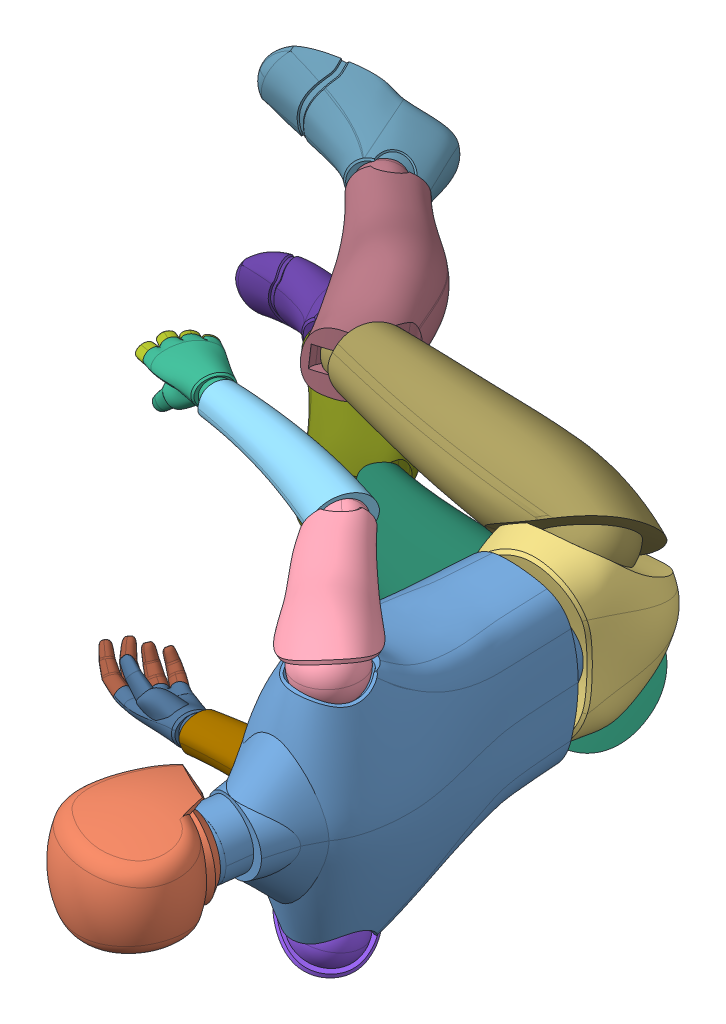
SolidWorks assembly Articulated_Dummy, configuration Default. Lengths in mm.
Overall size (1080.62 622.28 1340.25).
19 component instances, 17 part files, 18 mates.
Components (placement in the parent):
- Torso-1: Torso [Default] at origin size (276.17 406.18 676.75)
- Head-1: Head [Default] at (272.4966 0 13.9002) x (0.984808 0 0.173648) z (-0.173648 0 0.984808) size (223.51 154.11 248.99)
- Pelvis-1: Pelvis [Default] at (-175.9416 -0.0047 21.1469) x (0.984808 0 -0.173648) z (0.173648 0 0.984808) size (220.9 294.19 237.82)
- UpperArm_R-1: UpperArm_R [Default] at (-967.4121 -31.8704 494.9868) x (0.686668 0.032226 -0.726256) z (0.725991 0.021461 0.68737) size (145.29 112.21 352.1)
- LowerArm_R-1: LowerArm_R [Default] at (-1163.8165 -131.5552 990.6603) x (0.282282 -0.015764 -0.959202) z (0.953344 0.116147 0.278649) size (97.1 110.82 304.02)
- Hand_R-1: Hand_R [Default] at (-1071.8641 -48.9337 667.7427) x (0.586634 0.138363 -0.797945) z (0.805428 0.00317 0.592685) size (143.51 200.25 239.15)
  - Hand_R-1: Hand_R [Default] at origin size (143.51 200.25 232.94)
  - Fingers_R-1: Fingers_R [Default] at origin size (103.08 62.21 73.67)
- UpperArm_L-1: UpperArm_L [Default] at (-963.6086 40.2091 492.5524) x (0.655397 -0.202373 -0.727667) z (0.740186 -0.019578 0.672117) size (149.95 126.7 354.11)
- LowerArm_L-1: LowerArm_L [Default] at (-1215.8864 -1.0102 1100.795) x (0.200712 0.118224 -0.972491) z (0.979571 -0.01162 0.200761) size (97.1 110.82 304.02)
- Hand_L-1: Hand_L [Default] at (-1163.1688 -95.7629 792.4915) x (0.487614 -0.083042 -0.869101) z (0.870629 0.120485 0.476958) size (143.54 200.25 239.15)
  - Hand_L-1: Hand_L [Default] at origin size (143.54 200.25 232.94)
  - Fingers_L-1: Fingers_L [Default] at origin size (103.08 62.28 73.68)
- UpperLeg_R-1: UpperLeg_R [Default] at (-874.2977 48.5468 874.3966) x (0.108908 -0.602397 -0.790732) z (0.990819 0.001682 0.135184) size (212.64 165.47 563.01)
- LowerLeg_R-1: LowerLeg_R [Default] at (-712.3034 -40.8146 511.4118) x (0.771505 0.113631 -0.625994) z (0.620305 0.084374 0.77981) size (159.05 194.06 506.09)
- Foot_R-1: Foot_R [Default] at (-721.4345 -28.8172 498.7546) x (0.899051 -0.06744 -0.432619) z (0.434787 0.020963 0.900289) size (250.01 160.41 191.51)
- UpperLeg_L-1: UpperLeg_L [Default] at (-872.8456 -21.2577 898.3064) x (0.106044 0.59845 -0.794111) z (0.99355 -0.031522 0.108922) size (212.64 165.47 563.01)
- LowerLeg_L-1: LowerLeg_L [Default] at (-745.7676 -14.2143 531.1085) x (0.689228 -0.309105 -0.655301) z (0.704606 0.075229 0.7056) size (159.05 194.91 471.32)
- Foot_L-1: Foot_L [Default] at (-717.1717 -4.9666 523.6228) x (0.96643 -0.093697 -0.239235) z (0.236502 -0.039427 0.970831) size (250.8 160.43 191.19)
Mates (geometry in assembly coordinates):
- Coincident1: coincident: point of Torso-1; point of Head-1
- Parallel1: parallel aligned: plane of Head-1 through (272.4966 0 13.9002) normal (0 1 0)
- LimitAngle1: limit planar angle = 0.174533 rad aligned: plane of Head-1 through (272.4966 0 13.9002) normal (-0.173648 0 0.984808)
- Coincident5: coincident: point of Torso-1; point of Pelvis-1
- Parallel3: parallel aligned: plane of Pelvis-1 through (-175.9416 -0.0047 21.1469) normal (0 1 0)
- LimitAngle2: limit planar angle = 0.174533 rad aligned: plane of Pelvis-1 through (-175.9416 -0.0047 21.1469) normal (0.173648 0 0.984808); plane of Torso-1 through (0 0 0) normal (0 0 1)
- Coincident6: coincident: point of UpperArm_R-1; point of Torso-1
- Coincident7: coincident: point of UpperArm_R-1; point of LowerArm_R-1
- Coincident8: coincident: point of LowerArm_R-1; point of Hand_R-1
- Coincident9: coincident: point of UpperArm_L-1; point of Torso-1
- Coincident10: coincident: point of UpperArm_L-1; point of LowerArm_L-1
- Coincident11: coincident: point of LowerArm_L-1; point of Hand_L-1
- Coincident12: coincident: point of UpperLeg_R-1; point of Pelvis-1
- Coincident13: coincident: point of LowerLeg_R-1; point of UpperLeg_R-1
- Coincident14: coincident: point of LowerLeg_R-1; point of Foot_R-1
- Coincident15: coincident: point of Pelvis-1; point of UpperLeg_L-1
- Coincident16: coincident: point of LowerLeg_L-1; point of UpperLeg_L-1
- Coincident17: coincident: point of LowerLeg_L-1; point of Foot_L-1
